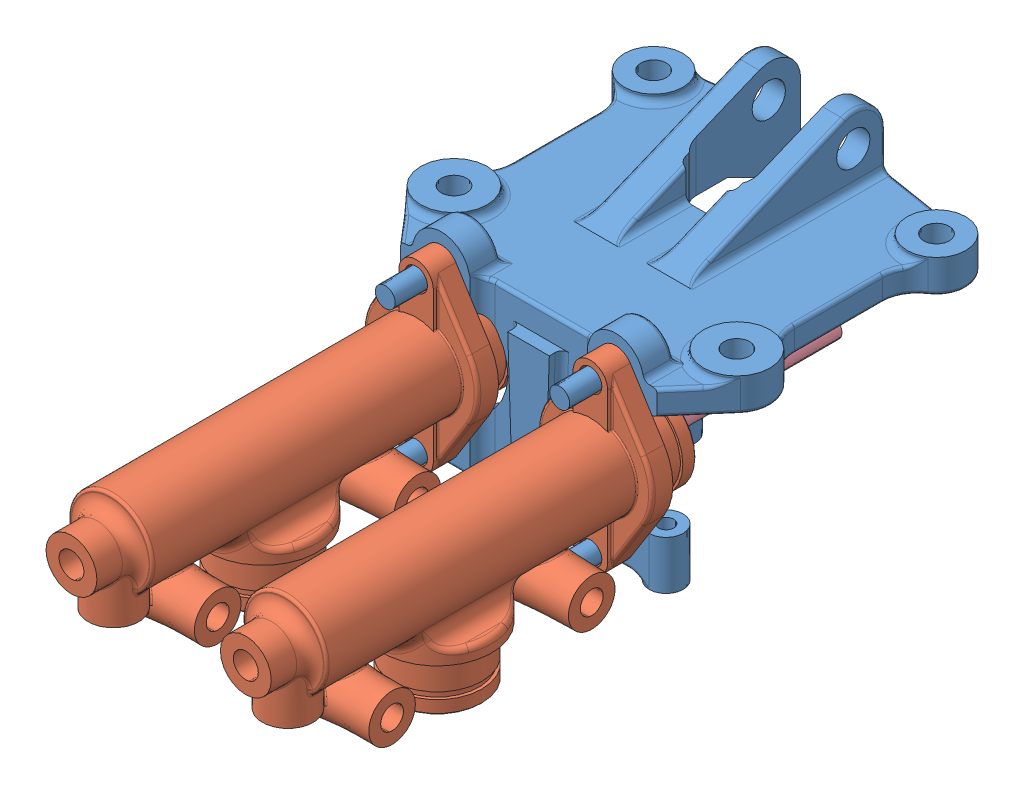
SolidWorks assembly newBrakeMS_assem, configuration Default. Lengths in mm.
Overall size (133.35 95.19 257.05).
9 component instances, 4 part files, 6 mates.
Components (placement in the parent):
- pedalmount-1: pedalmount [Default] at (-8.0254 86.5254 126.5371) size (133.35 93.62 137.28)
- mastercylinder asm-1: mastercylinder asm [Default] at (25.2486 67.4754 134.5381) x (1 0 0) z (0 0 -1) size (45.21 75.99 223.71)
  - mastercylinder-1: mastercylinder [Default] at origin size (45.21 75.99 154.88)
  - mastercylinder retaining washer-1: mastercylinder retaining washer [Default] at (0 0 17.145) size (20.83 20.83 1.91)
  - mastercylinder pushrod-1: mastercylinder pushrod [Default] at (0 0 90.551) x (-0.12806 0.991766 0) z (0 0 1) size (10.67 10.67 107.24)
- mastercylinder asm-2: mastercylinder asm [Default] at (91.7966 67.4754 134.5381) x (1 0 0) z (0 0 -1) size (45.21 75.99 223.71)
  - mastercylinder-1: mastercylinder [Default] at origin size (45.21 75.99 154.88)
  - mastercylinder retaining washer-1: mastercylinder retaining washer [Default] at (0 0 17.145) size (20.83 20.83 1.91)
  - mastercylinder pushrod-1: mastercylinder pushrod [Default] at (0 0 90.551) x (-0.12806 0.991766 0) z (0 0 1) size (10.67 10.67 107.24)
Mates (geometry in assembly coordinates):
- Concentric2: concentric anti-aligned: cylinder of pedalmount-1 through (25.2486 96.0504 147.9239) axis (0 0 -1) radius 3.81; cylinder of mastercylinder asm-1/mastercylinder-1 through (25.2486 96.0504 126.5371) axis (0 0 1) radius 4.3656
- Coincident2: coincident anti-aligned: plane of pedalmount-1 through (9.7546 96.0504 126.5371) normal (0 0 1); plane of mastercylinder asm-1/mastercylinder-1 through (25.2486 38.9004 126.5371) normal (0 0 -1)
- Concentric3: concentric anti-aligned: cylinder of pedalmount-1 through (25.2486 38.9004 147.9239) axis (0 0 -1) radius 3.81; cylinder of mastercylinder asm-1/mastercylinder-1 through (25.2486 38.9004 126.5371) axis (0 0 1) radius 4.3656
- Concentric4: concentric anti-aligned: cylinder of pedalmount-1 through (91.7966 96.0504 147.9239) axis (0 0 -1) radius 3.81; cylinder of mastercylinder asm-2/mastercylinder-1 through (91.7966 96.0504 126.5371) axis (0 0 1) radius 4.3656
- Concentric5: concentric anti-aligned: cylinder of pedalmount-1 through (91.7966 38.9004 147.9239) axis (0 0 -1) radius 3.81; cylinder of mastercylinder asm-2/mastercylinder-1 through (91.7966 38.9004 126.5371) axis (0 0 1) radius 4.3656
- Coincident3: coincident anti-aligned: plane of pedalmount-1 through (81.1286 96.0504 126.5371) normal (0 0 1); plane of mastercylinder asm-2/mastercylinder-1 through (91.7966 38.9004 126.5371) normal (0 0 -1)
